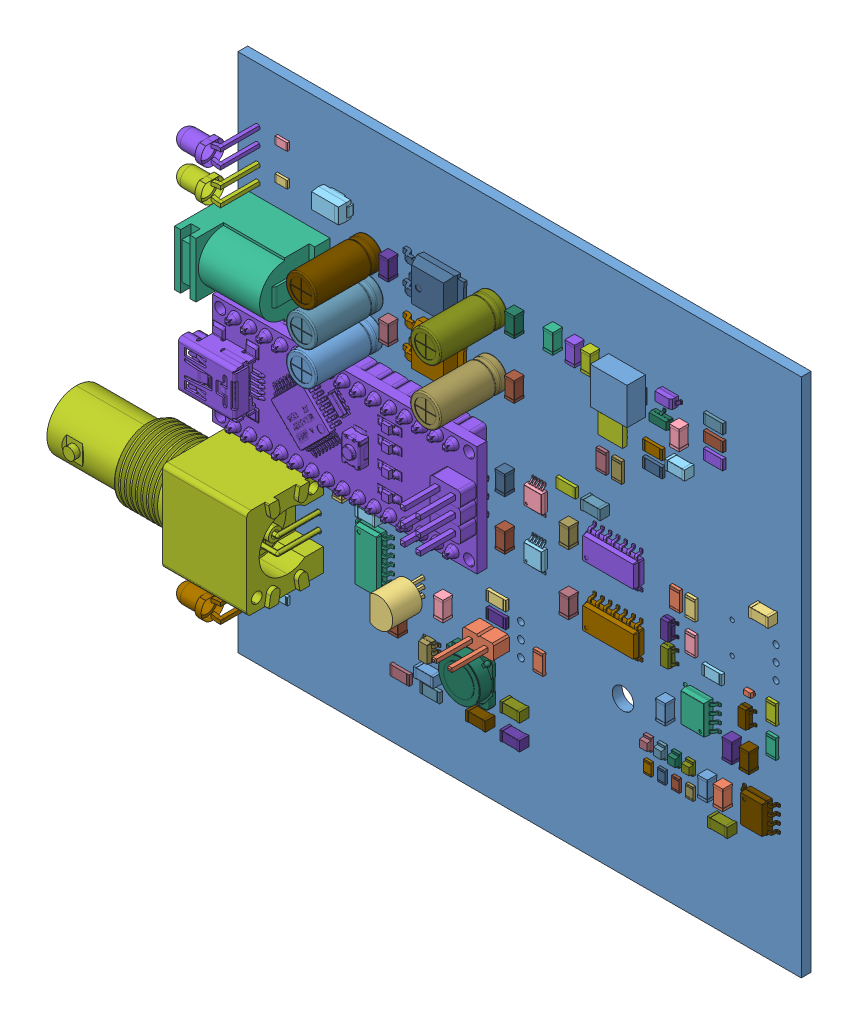
SolidWorks assembly PCBA, configuration Domyślna. Lengths in mm.
Overall size (111.73 89 18.8).
103 component instances, 99 part files, 0 mates.
Components (placement in the parent):
- PCBA.step-1: PCBA.step [Domyślna] at origin size (111.73 89 18.8)
  - Board_Geoms_e78a.step-1: Board_Geoms_e78a.step [Domyślna] at origin size (92 89 1.6)
    - Pcb_e78a.step-1: Pcb_e78a.step [Domyślna] at (-104.194 136.428 0) size (92 89 1.6)
    - PCB_Sketch_e78a.step-1: PCB_Sketch_e78a.step [Domyślna] at origin (suppressed, hidden)
  - Step_Models_e78a.step-1: Step_Models_e78a.step [Domyślna] at origin size (108.33 68.14 18.8)
    - Top_e78a.step-1: Top_e78a.step [Domyślna] at origin size (108.33 68.14 18.8)
      - R28_R_1206_3216Metric_60135E3C.step-1: R28_R_1206_3216Metric_60135E3C.step [Domyślna] at (49.53 8.636 0) x (0 1 0) z (0 0 1) size (3.2 1.6 0.55)
      - R27_R_0805_2012Metric_5F3C1C00.step-1: R27_R_0805_2012Metric_5F3C1C00.step [Domyślna] at (7.493 55.626 0) size (2 1.2 0.45)
      - R26_R_0805_2012Metric_5F3C1C30.step-1: R26_R_0805_2012Metric_5F3C1C30.step [Domyślna] at (7.493 60.96 0) size (2 1.2 0.45)
      - R25_R_0805_2012Metric_5F3C1E7C.step-1: R25_R_0805_2012Metric_5F3C1E7C.step [Domyślna] at (7.5415 -3.302 0) size (2 1.2 0.45)
      - R24_R_0805_2012Metric_60130AB3.step-1: R24_R_0805_2012Metric_60130AB3.step [Domyślna] at (7.493 2.032 0) size (2 1.2 0.45)
      - D12_LED_D3.0mm_Horizontal_O1.27mm_Z6.0mm_5F3C2200.step-1: D12_LED_D3.0mm_Horizontal_O1.27mm_Z6.0mm_5F3C2200.step [Domyślna] at (3.175 55.626 0) x (0 -1 0) z (0 0 1) size (3.48 6.88 9.91)
      - D11_LED_D3.0mm_Horizontal_O1.27mm_Z6.0mm_5F3C2185.step-1: D11_LED_D3.0mm_Horizontal_O1.27mm_Z6.0mm_5F3C2185.step [Domyślna] at (3.175 60.96 0) x (0 -1 0) z (0 0 1) size (3.48 6.88 9.91)
      - D10_LED_D3.0mm_Horizontal_O1.27mm_Z6.0mm_5F3C56BC.step-1: D10_LED_D3.0mm_Horizontal_O1.27mm_Z6.0mm_5F3C56BC.step [Domyślna] at (3.175 -3.302 0) x (0 -1 0) z (0 0 1) size (3.48 6.88 9.91)
      - D9_LED_D3.0mm_Horizontal_O1.27mm_Z6.0mm_5F3C1D9F.step-1: D9_LED_D3.0mm_Horizontal_O1.27mm_Z6.0mm_5F3C1D9F.step [Domyślna] at (3.175 2.032 0) x (0 -1 0) z (0 0 1) size (3.48 6.88 9.91)
      - C31_C_1206_3216Metric_5F0E55A1.step-1: C31_C_1206_3216Metric_5F0E55A1.step [Domyślna] at (26.924 3.302 0) x (0 -1 0) z (0 0 1) size (3.2 1.6 1.6)
      - IC12_SOT_23_6_5F31C27B.step-1: IC12_SOT_23_6_5F31C27B.step [Domyślna] at (31.75 1.651 0) x (-1 0 0) z (0 0 1) size (2.8 2.9 1.55)
      - R23_R_1206_3216Metric_5F31C265.step-1: R23_R_1206_3216Metric_5F31C265.step [Domyślna] at (26.924 -4.445 0) size (3.2 1.6 0.55)
      - R22_R_1206_3216Metric_5F31DD4A.step-1: R22_R_1206_3216Metric_5F31DD4A.step [Domyślna] at (31.877 -4.445 0) x (-1 0 0) z (0 0 1) size (3.2 1.6 0.55)
      - L2_Sf_fd_sp_5F31CDB4[2].step-1: L2_Sf_fd_sp_5F31CDB4[2].step [Domyślna] at (38.608 1.651 0.0508) size (7 7 2.5)
      - C36_C_1206_3216Metric_5F31B990.step-1: C36_C_1206_3216Metric_5F31B990.step [Domyślna] at (45.974 0.381 0) size (3.2 1.6 1.6)
      - C35_C_1206_3216Metric_5F31B97F.step-1: C35_C_1206_3216Metric_5F31B97F.step [Domyślna] at (45.974 -3.683 0) size (3.2 1.6 1.6)
      - C34_C_1206_3216Metric_5F31B96E.step-1: C34_C_1206_3216Metric_5F31B96E.step [Domyślna] at (40.386 -3.683 0) x (-1 0 0) z (0 0 1) size (3.2 1.6 1.6)
      - C33_C_1206_3216Metric_5F31B95D.step-1: C33_C_1206_3216Metric_5F31B95D.step [Domyślna] at (31.877 -1.778 0) x (-1 0 0) z (0 0 1) size (3.2 1.6 1.6)
      - C32_C_1206_3216Metric_5F2DB7B1.step-1: C32_C_1206_3216Metric_5F2DB7B1.step [Domyślna] at (5.334 24.384 0) x (-1 0 0) z (0 0 1) size (3.2 1.6 1.6)
      - R21_R_1206_3216Metric_5F2CE966.step-1: R21_R_1206_3216Metric_5F2CE966.step [Domyślna] at (42.672 13.97 0) size (3.2 1.6 0.55)
      - IC8_DS1124U-25+_5F0C9A39.step-1: IC8_DS1124U-25+_5F0C9A39.step [Domyślna] at (49.222 31.78 0) x (0 1 0) z (0 0 1) size (4.9 3 1.1)
      - IC7_DS1124U-25+_5F0C50CD.step-1: IC7_DS1124U-25+_5F0C50CD.step [Domyślna] at (49.222 23.652 0) x (0 1 0) z (0 0 1) size (4.9 3 1.1)
      - IC2_TLV3501AIDR_5F0DC31C.step-1: IC2_TLV3501AIDR_5F0DC31C.step [Domyślna] at (75.944 15.19 0) x (-1 0 0) z (0 0 1) size (6 4.9 1.75)
      - IC1_MAX1932ETC+_5F0DC301.step-1: IC1_MAX1932ETC+_5F0DC301.step [Domyślna] at (61.614 48.076 0) size (4.1 4.1 0.8)
      - D1_BAT46W-E3-08_5F0B6668.step-1: D1_BAT46W-E3-08_5F0B6668.step [Domyślna] at (70.758 56.712 0) x (-1 0 0) z (0 0 1) size (3.7 1.55 1.35)
      - R20_R_0805_2012Metric_5F2C1AB9.step-1: R20_R_0805_2012Metric_5F2C1AB9.step [Domyślna] at (67.31 2.54 0) x (0 -1 0) z (0 0 1) size (2 1.2 0.45)
      - R19_R_0805_2012Metric_5F2C1B19.step-1: R19_R_0805_2012Metric_5F2C1B19.step [Domyślna] at (69.596 2.54 0) x (0 -1 0) z (0 0 1) size (2 1.2 0.45)
      - R16_R_0805_2012Metric_5F2C1B49.step-1: R16_R_0805_2012Metric_5F2C1B49.step [Domyślna] at (71.882 2.54 0) x (0 -1 0) z (0 0 1) size (2 1.2 0.45)
      - R13_R_0805_2012Metric_5F2C1AE9.step-1: R13_R_0805_2012Metric_5F2C1AE9.step [Domyślna] at (74.168 2.54 0) x (0 -1 0) z (0 0 1) size (2 1.2 0.45)
      - D8_LED_0805_2012Metric_5F2C1BB1.step-1: D8_LED_0805_2012Metric_5F2C1BB1.step [Domyślna] at (67.31 6.096 0) x (0 1 0) z (0 0 1) size (2 1.25 1.1)
      - D7_LED_0805_2012Metric_5F2C1BE7.step-1: D7_LED_0805_2012Metric_5F2C1BE7.step [Domyślna] at (69.596 6.096 0) x (0 1 0) z (0 0 1) size (2 1.25 1.1)
      - D6_LED_0805_2012Metric_5F2C1B7B.step-1: D6_LED_0805_2012Metric_5F2C1B7B.step [Domyślna] at (71.882 6.096 0) x (0 1 0) z (0 0 1) size (2 1.25 1.1)
      - D5_LED_0805_2012Metric_5F2B9F6D.step-1: D5_LED_0805_2012Metric_5F2B9F6D.step [Domyślna] at (74.168 6.096 0) x (0 1 0) z (0 0 1) size (2 1.25 1.1)
      - R10_R_1206_3216Metric_5F2BA4CF.step-1: R10_R_1206_3216Metric_5F2BA4CF.step [Domyślna] at (42.672 11.43 0) size (3.2 1.6 0.55)
      - IC5_SOIC_8_39x49mm_P127mm_5F2C782A.step-1: IC5_SOIC_8_39x49mm_P127mm_5F2C782A.step [Domyślna] at (85.598 5.788 0) size (6 4.9 1.75)
      - C30_C_Radial_D50mm_H110mm_P200mm_5F0E5590.step-1: C30_C_Radial_D50mm_H110mm_P200mm_5F0E5590.step [Domyślna] at (21.336 42.164 0) x (0 -1 0) z (0 0 1) size (6.29 6.83 13)
      - J2_PinHeader_1x02_P254mm_Vertical_6016EDB8.step-1: J2_PinHeader_1x02_P254mm_Vertical_6016EDB8.step [Domyślna] at (40.513 8.382 0) x (0 1 0) z (0 0 1) size (2.54 5.08 11.54)
      - IC11_TO-92_Inline_Narrow_5F0E2760.step-1: IC11_TO-92_Inline_Narrow_5F0E2760.step [Domyślna] at (30.172 10.698 0) x (0 -1 0) z (0 0 1) size (4.83 3.75 9.8)
      - C29_C_1206_3216Metric_5F0F3A25.step-1: C29_C_1206_3216Metric_5F0F3A25.step [Domyślna] at (34.29 9.144 0) x (0 -1 0) z (0 0 1) size (3.2 1.6 1.6)
      - C28_C_1206_3216Metric_5F0EE626.step-1: C28_C_1206_3216Metric_5F0EE626.step [Domyślna] at (22.352 16.256 0) x (-1 0 0) z (0 0 1) size (3.2 1.6 1.6)
      - IC10_SOIC_14_39x87mm_P127mm_5F0D8E3B.step-1: IC10_SOIC_14_39x87mm_P127mm_5F0D8E3B.step [Domyślna] at (22.617 10.19 0) size (6 8.7 1.75)
      - R9_R_1206_3216Metric_5F0C53DD.step-1: R9_R_1206_3216Metric_5F0C53DD.step [Domyślna] at (54.048 35.59 0) size (3.2 1.6 0.55)
      - IC9_SOIC_14_39x87mm_P127mm_5F0C510A.step-1: IC9_SOIC_14_39x87mm_P127mm_5F0C510A.step [Domyślna] at (62.176 29.748 0) x (0 1 0) z (0 0 1) size (6 8.7 1.75)
      - IC6_SOIC_14_39x87mm_P127mm_5F0C50B0.step-1: IC6_SOIC_14_39x87mm_P127mm_5F0C50B0.step [Domyślna] at (62.176 19.842 0) x (0 1 0) z (0 0 1) size (6 8.7 1.75)
      - C27_C_1206_3216Metric_5F0C4ED7.step-1: C27_C_1206_3216Metric_5F0C4ED7.step [Domyślna] at (44.396 32.034 0) x (0 -1 0) z (0 0 1) size (3.2 1.6 1.6)
      - C26_C_1206_3216Metric_5F0C4EC6.step-1: C26_C_1206_3216Metric_5F0C4EC6.step [Domyślna] at (44.396 23.906 0) x (0 -1 0) z (0 0 1) size (3.2 1.6 1.6)
      - C25_C_1206_3216Metric_5F0C4EB5.step-1: C25_C_1206_3216Metric_5F0C4EB5.step [Domyślna] at (54.81 29.748 0) x (0 -1 0) z (0 0 1) size (3.2 1.6 1.6)
      - C24_C_1206_3216Metric_5F0C4EA4.step-1: C24_C_1206_3216Metric_5F0C4EA4.step [Domyślna] at (54.81 19.842 0) x (0 -1 0) z (0 0 1) size (3.2 1.6 1.6)
      - C23_C_1206_3216Metric_5F0C4E93.step-1: C23_C_1206_3216Metric_5F0C4E93.step [Domyślna] at (59.128 35.59 0) size (3.2 1.6 1.6)
      - R4_R_1206_3216Metric_5F0BCC0F.step-1: R4_R_1206_3216Metric_5F0BCC0F.step [Domyślna] at (33.474 24.414 0) size (3.2 1.6 0.55)
      - C22_C_1206_3216Metric_5F2C77F1.step-1: C22_C_1206_3216Metric_5F2C77F1.step [Domyślna] at (79.886 1.016 0) x (-1 0 0) z (0 0 1) size (3.2 1.6 1.6)
      - C21_C_1206_3216Metric_5F0BC811.step-1: C21_C_1206_3216Metric_5F0BC811.step [Domyślna] at (81.452 12.646 0) x (0 -1 0) z (0 0 1) size (3.2 1.6 1.6)
      - C20_C_1206_3216Metric_5F0BC800.step-1: C20_C_1206_3216Metric_5F0BC800.step [Domyślna] at (84.246 12.646 0) x (0 -1 0) z (0 0 1) size (3.2 1.6 1.6)
      - C19_C_1206_3216Metric_5F2C7791.step-1: C19_C_1206_3216Metric_5F2C7791.step [Domyślna] at (77.44 5.28 0) x (0 -1 0) z (0 0 1) size (3.2 1.6 1.6)
      - C18_C_1206_3216Metric_5F2C77C1.step-1: C18_C_1206_3216Metric_5F2C77C1.step [Domyślna] at (79.98 5.28 0) x (0 -1 0) z (0 0 1) size (3.2 1.6 1.6)
      - C17_C_1206_3216Metric_5F0BB606.step-1: C17_C_1206_3216Metric_5F0BB606.step [Domyślna] at (17.78 17.78 0) x (0 -1 0) z (0 0 1) size (3.2 1.6 1.6)
      - C16_C_1206_3216Metric_5F0BBC4D.step-1: C16_C_1206_3216Metric_5F0BBC4D.step [Domyślna] at (33.728 18.572 0) size (3.2 1.6 1.6)
      - D4_D_SMA_5F0B762E.step-1: D4_D_SMA_5F0B762E.step [Domyślna] at (16.456 57.18 0) x (-1 0 0) z (0 0 1) size (5 2.7 2.22)
      - J4_CUI_DEVICES_PJ-102AH_5F0EDE56.step-1: J4_CUI_DEVICES_PJ-102AH_5F0EDE56.step [Domyślna] at (0.7334 46.736 6.5786) x (-1 0 0) z (0 1 0) size (14.4 14.5 9.4)
      - J3_73100-0131_5F0BBBC4.step-1: J3_73100-0131_5F0BBBC4.step [Domyślna] at (-2.4892 11.43 6.6548) x (0 -1 0) z (-1 0 0) size (14.76 18.23 35.18)
      - A1_arduino_nano_5F2D0076.step-1: A1_arduino_nano_5F2D0076.step [Domyślna] at (39.824 36.86 3) x (-1 0 0) z (0 1 0) size (45 18.6 18)
      - IC4_TO_252_2_5F0B63C8.step-1: IC4_TO_252_2_5F0B63C8.step [Domyślna] at (32.458 44.48 0) size (9.9 6.5 2.32)
      - IC3_TO_252_2_5F0B6491.step-1: IC3_TO_252_2_5F0B6491.step [Domyślna] at (32.458 53.624 0) size (9.9 6.5 2.32)
      - C15_C_1206_3216Metric_5F0B641E.step-1: C15_C_1206_3216Metric_5F0B641E.step [Domyślna] at (45.92 46.004 0) x (0 1 0) z (0 0 1) size (3.2 1.6 1.6)
      - C14_C_Radial_D50mm_H110mm_P200mm_5F0B62A3.step-1: C14_C_Radial_D50mm_H110mm_P200mm_5F0B62A3.step [Domyślna] at (41.602 44.48 0) x (0 1 0) z (0 0 1) size (6.29 6.83 13)
      - C13_C_1206_3216Metric_5F0B644E.step-1: C13_C_1206_3216Metric_5F0B644E.step [Domyślna] at (25.346 43.718 0) x (0 1 0) z (0 0 1) size (3.2 1.6 1.6)
      - C12_C_Radial_D50mm_H110mm_P200mm_5F0B62BE.step-1: C12_C_Radial_D50mm_H110mm_P200mm_5F0B62BE.step [Domyślna] at (21.336 45.72 0) x (0 1 0) z (0 0 1) size (6.29 6.83 13)
      - C11_C_1206_3216Metric_5F0B62E0.step-1: C11_C_1206_3216Metric_5F0B62E0.step [Domyślna] at (45.92 55.148 0) x (0 1 0) z (0 0 1) size (3.2 1.6 1.6)
      - C10_C_Radial_D50mm_H110mm_P200mm_5F0B6309.step-1: C10_C_Radial_D50mm_H110mm_P200mm_5F0B6309.step [Domyślna] at (41.602 53.624 0) x (0 1 0) z (0 0 1) size (6.29 6.83 13)
      - C9_C_1206_3216Metric_5F0B6385.step-1: C9_C_1206_3216Metric_5F0B6385.step [Domyślna] at (25.346 52.862 0) x (0 1 0) z (0 0 1) size (3.2 1.6 1.6)
      - C8_C_Radial_D50mm_H110mm_P200mm_5F0B6324.step-1: C8_C_Radial_D50mm_H110mm_P200mm_5F0B6324.step [Domyślna] at (21.282 51.338 0) x (0 1 0) z (0 0 1) size (6.29 6.83 13)
      - C7_C_1206_3216Metric_5F0C274F.step-1: C7_C_1206_3216Metric_5F0C274F.step [Domyślna] at (70.61 12.7 0) x (0 -1 0) z (0 0 1) size (3.2 1.6 1.6)
      - R18_R_1206_3216Metric_5F0A53A7.step-1: R18_R_1206_3216Metric_5F0A53A7.step [Domyślna] at (71.828 28.732 0) x (0 1 0) z (0 0 1) size (3.2 1.6 0.55)
      - R17_R_1206_3216Metric_5F0A5396.step-1: R17_R_1206_3216Metric_5F0A5396.step [Domyślna] at (74.368 28.732 0) x (0 1 0) z (0 0 1) size (3.2 1.6 0.55)
      - R15_R_1206_3216Metric_5F0A5385.step-1: R15_R_1206_3216Metric_5F0A5385.step [Domyślna] at (74.368 23.652 0) x (0 -1 0) z (0 0 1) size (3.2 1.6 0.55)
      - R14_R_1206_3216Metric_5F0A5374.step-1: R14_R_1206_3216Metric_5F0A5374.step [Domyślna] at (77.924 21.112 0) size (3.2 1.6 0.55)
      - R12_R_1206_3216Metric_5F0A5363.step-1: R12_R_1206_3216Metric_5F0A5363.step [Domyślna] at (87.576 15.778 0) x (0 -1 0) z (0 0 1) size (3.2 1.6 0.55)
      - R11_R_1206_3216Metric_5F0D1442.step-1: R11_R_1206_3216Metric_5F0D1442.step [Domyślna] at (87.576 20.604 0) x (0 -1 0) z (0 0 1) size (3.2 1.6 0.55)
      - R8_R_1206_3216Metric_5F0B69A0.step-1: R8_R_1206_3216Metric_5F0B69A0.step [Domyślna] at (78.124 51.632 0) size (3.2 1.6 0.55)
      - R7_R_1206_3216Metric_5F0B6970.step-1: R7_R_1206_3216Metric_5F0B6970.step [Domyślna] at (68.218 48.076 0) size (3.2 1.6 0.55)
      - R6_R_1206_3216Metric_5F0B680B.step-1: R6_R_1206_3216Metric_5F0B680B.step [Domyślna] at (68.218 45.536 0) x (-1 0 0) z (0 0 1) size (3.2 1.6 0.55)
      - R5_R_1206_3216Metric_5F0B67AB.step-1: R5_R_1206_3216Metric_5F0B67AB.step [Domyślna] at (78.124 54.172 0) x (-1 0 0) z (0 0 1) size (3.2 1.6 0.55)
      - R3_R_1206_3216Metric_5F0B6940.step-1: R3_R_1206_3216Metric_5F0B6940.step [Domyślna] at (62.376 42.234 0) x (0 1 0) z (0 0 1) size (3.2 1.6 0.55)
      - R2_R_1206_3216Metric_5F0B6910.step-1: R2_R_1206_3216Metric_5F0B6910.step [Domyślna] at (59.836 42.234 0) x (0 -1 0) z (0 0 1) size (3.2 1.6 0.55)
      - R1_R_1206_3216Metric_5F0B68E0.step-1: R1_R_1206_3216Metric_5F0B68E0.step [Domyślna] at (78.124 56.712 0) size (3.2 1.6 0.55)
      - Q4_SOT_23_5F0B68A8.step-1: Q4_SOT_23_5F0B68A8.step [Domyślna] at (69.742 53.156 0) x (0 1 0) z (0 0 1) size (2.5 3 1.2)
      - Q3_SOT_23_5F0B91D4.step-1: Q3_SOT_23_5F0B91D4.step [Domyślna] at (70.812 20.35 0) x (-1 0 0) z (0 0 1) size (2.5 3 1.2)
      - Q2_SOT_23_5F0B9198.step-1: Q2_SOT_23_5F0B9198.step [Domyślna] at (70.812 24.16 0) x (-1 0 0) z (0 0 1) size (2.5 3 1.2)
      - Q1_SOT_23_5F0A528B.step-1: Q1_SOT_23_5F0A528B.step [Domyślna] at (83.512 18.064 0) x (-1 0 0) z (0 0 1) size (2.5 3 1.2)
      - L1_#A921CY-101M=P3_5F0B67DB.step-1: L1_#A921CY-101M=P3_5F0B67DB.step [Domyślna] at (63.646 54.68 0) size (6.4 6 3.1)
      - D2_D_SOD_523_5F0A520A.step-1: D2_D_SOD_523_5F0A520A.step [Domyślna] at (83.766 21.366 0) x (-1 0 0) z (0 0 1) size (1.6 0.8 0.63)
      - C6_C_1206_3216Metric_5F0A72A1.step-1: C6_C_1206_3216Metric_5F0A72A1.step [Domyślna] at (86.56 34.066 0) size (3.2 1.6 1.6)
      - C5_C_1206_3216Metric_5F0A51C2.step-1: C5_C_1206_3216Metric_5F0A51C2.step [Domyślna] at (72.844 52.608 0) x (0 1 0) z (0 0 1) size (3.2 1.6 1.6)
      - C4_C_1206_3216Metric_5F0B66CA.step-1: C4_C_1206_3216Metric_5F0B66CA.step [Domyślna] at (72.914 48.076 0) x (-1 0 0) z (0 0 1) size (3.2 1.6 1.6)
      - C3_C_1206_3216Metric_5F0B66FA.step-1: C3_C_1206_3216Metric_5F0B66FA.step [Domyślna] at (52.216 55.95 0) x (0 1 0) z (0 0 1) size (3.2 1.6 1.6)
      - C2_C_1206_3216Metric_5F0B669A.step-1: C2_C_1206_3216Metric_5F0B669A.step [Domyślna] at (58.312 55.95 0) x (0 1 0) z (0 0 1) size (3.2 1.6 1.6)
      - C1_C_1206_3216Metric_5F0B677B.step-1: C1_C_1206_3216Metric_5F0B677B.step [Domyślna] at (55.772 55.95 0) x (0 1 0) z (0 0 1) size (3.2 1.6 1.6)
